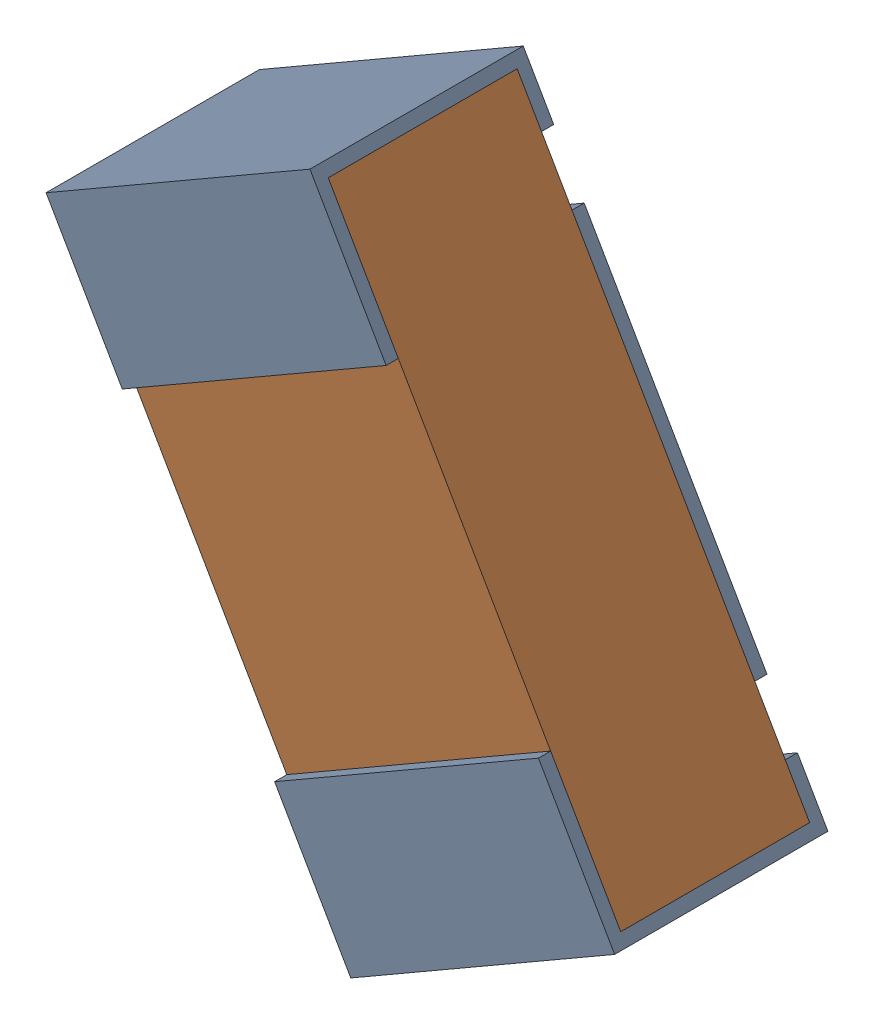
SolidWorks assembly R18, configuration Default. Lengths in mm.
Overall size (0.93 1.12 0.35).
3 component instances, 2 part files, 0 mates.
Components (placement in the parent):
- R18-subassembly-1-1: R18-subassembly-1 [Default] at (5.679 1.6229 -1.6307) x (-0.5 0.866025 0) z (-0.866025 -0.5 0) size (1 0.35 0.5)
  - 0402 resistor-1: 0402 resistor [Default] at origin size (1 0.35 0.5)
  - 0402 resistor-1-1: 0402 resistor-1 [Default] at origin size (0.96 0.31 0.5)
